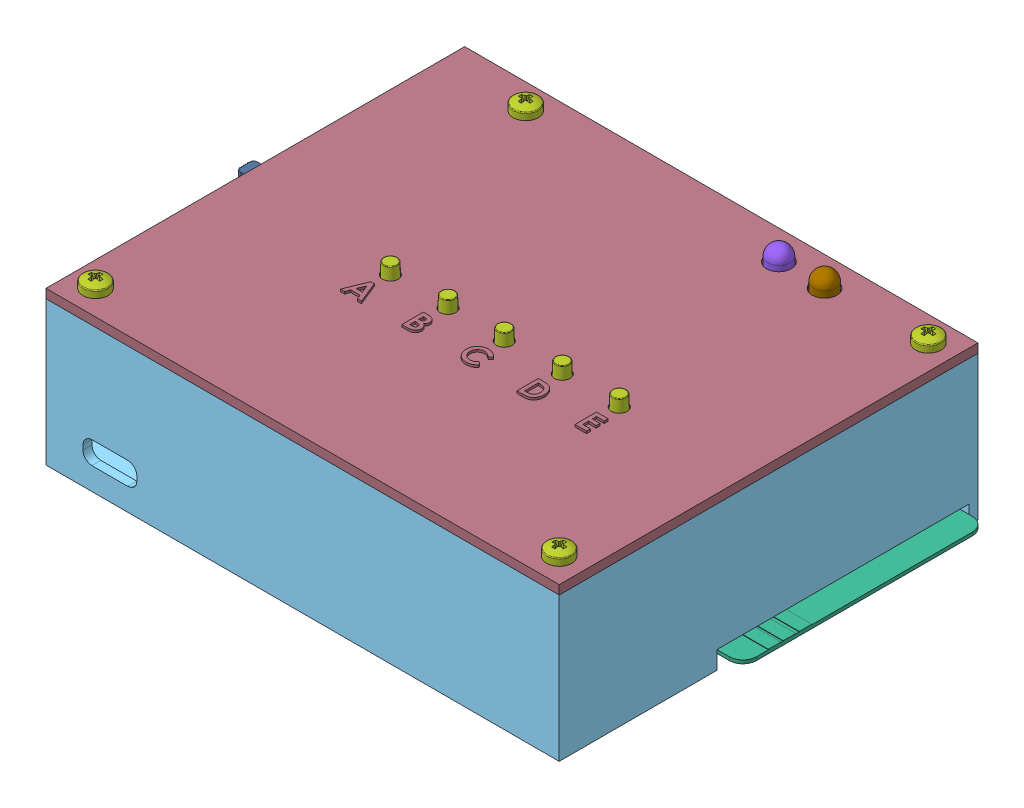
SolidWorks assembly Big_Assembly, configuration Default. Lengths in mm.
Overall size (123.61 37.68 93).
220 component instances, 55 part files, 99 mates.
Components (placement in the parent):
- ESP8266 v7-1: ESP8266 v7 [Default] at (-1.1537 3.2563 1.1041) x (0 0 -1) z (1 0 0) size (25.55 14.09 48.82)
  - ESP8266 v7-1: ESP8266 v7 [Default] at origin size (16.52 3.75 40.51)
  - micro usb v1-1: micro usb v1 [Default] at (12.6689 12.0548 1.95) x (0 -1 0) z (-1 0 0) size (3.25 6.18 8.01)
    - micro usb shell-1: micro usb shell [Default] at (10.11 -1.95 -0.7124) x (0 0 -1) z (0 1 0) size (8.01 2.95 5.63)
    - micro usb internal-1: micro usb internal [Default] at (10.36 -1.95 -0.7124) x (0 0 -1) z (0 1 0) size (6.9 2.9 4)
    - micro usb contact-1: micro usb contact [Default] at (10.36 -2.05 -2.0124) x (0 0 -1) z (0 1 0) size (0.2 1.3 4.65)
    - micro usb contact-2: micro usb contact [Default] at (10.36 -2.05 -1.3624) x (0 0 -1) z (0 1 0) size (0.2 1.3 4.65)
    - micro usb contact-3: micro usb contact [Default] at (10.36 -2.05 -0.7124) x (0 0 -1) z (0 1 0) size (0.2 1.3 4.65)
    - micro usb contact-4: micro usb contact [Default] at (10.36 -2.05 -0.0624) x (0 0 -1) z (0 1 0) size (0.2 1.3 4.65)
    - micro usb contact-5: micro usb contact [Default] at (10.36 -2.05 0.5876) x (0 0 -1) z (0 1 0) size (0.2 1.3 4.65)
  - switch v1-1: switch v1 [Default] at (-4.6798 0 12.1544) x (1 0 0) z (0 1 0) size (3 4.6 1.85)
  - switch v1 (1)-1: switch v1 (1) [Default] at (8.3273 0 12.1544) x (1 0 0) z (0 1 0) size (3 4.6 1.85)
  - Placa Base-1: Placa Base [Default] at origin size (25.55 11.43 48.19)
    - Placa Base-1: Placa Base [Default] at origin size (25.55 1.6 48.19)
    - Pin Header 1x15 TH Pitch 2.54mm v3 v1-1: Pin Header 1x15 TH Pitch 2.54mm v3 v1 [Default] at (24.996 0.1484 -10.5049) x (0 0 -1) z (0 1 0) size (38.1 2.59 11.43)
      - asm_pin-1: asm_pin [Default] at (-4.318 1.27 0.0014) x (1 0 0) z (0 0 -1) size (2.54 2.59 11.43)
        - spacer-1: spacer [Default] at origin size (2.54 2.59 2.54)
        - pin-1: pin [Default] at origin size (0.64 0.64 11.43)
      - asm_pin_1-1: asm_pin_1 [Default] at (-1.778 1.27 0.0014) x (1 0 0) z (0 0 -1) size (2.54 2.59 11.43)
        - spacer-1: spacer [Default] at origin size (2.54 2.59 2.54)
        - pin-1: pin [Default] at origin size (0.64 0.64 11.43)
      - asm_pin_2-1: asm_pin_2 [Default] at (0.762 1.27 0.0014) x (1 0 0) z (0 0 -1) size (2.54 2.59 11.43)
        - spacer-1: spacer [Default] at origin size (2.54 2.59 2.54)
        - pin-1: pin [Default] at origin size (0.64 0.64 11.43)
      - asm_pin_3-1: asm_pin_3 [Default] at (3.302 1.27 0.0014) x (1 0 0) z (0 0 -1) size (2.54 2.59 11.43)
        - spacer-1: spacer [Default] at origin size (2.54 2.59 2.54)
        - pin-1: pin [Default] at origin size (0.64 0.64 11.43)
      - asm_pin_4-1: asm_pin_4 [Default] at (5.842 1.27 0.0014) x (1 0 0) z (0 0 -1) size (2.54 2.59 11.43)
        - spacer-1: spacer [Default] at origin size (2.54 2.59 2.54)
        - pin-1: pin [Default] at origin size (0.64 0.64 11.43)
      - asm_pin_5-1: asm_pin_5 [Default] at (8.382 1.27 0.0014) x (1 0 0) z (0 0 -1) size (2.54 2.59 11.43)
        - spacer-1: spacer [Default] at origin size (2.54 2.59 2.54)
        - pin-1: pin [Default] at origin size (0.64 0.64 11.43)
      - asm_pin_6-1: asm_pin_6 [Default] at (10.922 1.27 0.0014) x (1 0 0) z (0 0 -1) size (2.54 2.59 11.43)
        - spacer-1: spacer [Default] at origin size (2.54 2.59 2.54)
        - pin-1: pin [Default] at origin size (0.64 0.64 11.43)
      - asm_pin_7-1: asm_pin_7 [Default] at (13.462 1.27 0.0014) x (1 0 0) z (0 0 -1) size (2.54 2.59 11.43)
        - spacer-1: spacer [Default] at origin size (2.54 2.59 2.54)
        - pin-1: pin [Default] at origin size (0.64 0.64 11.43)
      - asm_pin_8-1: asm_pin_8 [Default] at (16.002 1.27 0.0014) x (1 0 0) z (0 0 -1) size (2.54 2.59 11.43)
        - spacer-1: spacer [Default] at origin size (2.54 2.59 2.54)
        - pin-1: pin [Default] at origin size (0.64 0.64 11.43)
      - asm_pin_9-1: asm_pin_9 [Default] at (18.542 1.27 0.0014) x (1 0 0) z (0 0 -1) size (2.54 2.59 11.43)
        - spacer-1: spacer [Default] at origin size (2.54 2.59 2.54)
        - pin-1: pin [Default] at origin size (0.64 0.64 11.43)
      - asm_pin_10-1: asm_pin_10 [Default] at (21.082 1.27 0.0014) x (1 0 0) z (0 0 -1) size (2.54 2.59 11.43)
        - spacer-1: spacer [Default] at origin size (2.54 2.59 2.54)
        - pin-1: pin [Default] at origin size (0.64 0.64 11.43)
      - asm_pin_11-1: asm_pin_11 [Default] at (23.622 1.27 0.0014) x (1 0 0) z (0 0 -1) size (2.54 2.59 11.43)
        - spacer-1: spacer [Default] at origin size (2.54 2.59 2.54)
        - pin-1: pin [Default] at origin size (0.64 0.64 11.43)
      - asm_pin_12-1: asm_pin_12 [Default] at (26.1619 1.27 0.0014) x (1 0 0) z (0 0 -1) size (2.54 2.59 11.43)
        - spacer-1: spacer [Default] at origin size (2.54 2.59 2.54)
        - pin-1: pin [Default] at origin size (0.64 0.64 11.43)
      - asm_pin_13-1: asm_pin_13 [Default] at (28.702 1.27 0.0014) x (1 0 0) z (0 0 -1) size (2.54 2.59 11.43)
        - spacer-1: spacer [Default] at origin size (2.54 2.59 2.54)
        - pin-1: pin [Default] at origin size (0.64 0.64 11.43)
      - asm_pin_14-1: asm_pin_14 [Default] at (31.242 1.27 0.0014) x (1 0 0) z (0 0 -1) size (2.54 2.59 11.43)
        - spacer-1: spacer [Default] at origin size (2.54 2.59 2.54)
        - pin-1: pin [Default] at origin size (0.64 0.64 11.43)
    - Pin Header 1x15 TH Pitch 2.54mm v3 v1 (1) (1)-1: Pin Header 1x15 TH Pitch 2.54mm v3 v1 (1) (1) [Default] at (2.7074 0.1484 -10.5049) x (0 0 -1) z (0 1 0) size (38.1 2.59 11.43)
      - asm_pin (1) (1)-1: asm_pin (1) (1) [Default] at (-4.318 1.27 0.0014) x (1 0 0) z (0 0 -1) size (2.54 2.59 11.43)
        - spacer (1) (1)-1: spacer (1) (1) [Default] at origin size (2.54 2.59 2.54)
        - pin (1) (1)-1: pin (1) (1) [Default] at origin size (0.64 0.64 11.43)
      - asm_pin (1) (1)_1-1: asm_pin (1) (1)_1 [Default] at (-1.778 1.27 0.0014) x (1 0 0) z (0 0 -1) size (2.54 2.59 11.43)
        - spacer (1) (1)-1: spacer (1) (1) [Default] at origin size (2.54 2.59 2.54)
        - pin (1) (1)-1: pin (1) (1) [Default] at origin size (0.64 0.64 11.43)
      - asm_pin (1) (1)_2-1: asm_pin (1) (1)_2 [Default] at (0.762 1.27 0.0014) x (1 0 0) z (0 0 -1) size (2.54 2.59 11.43)
        - spacer (1) (1)-1: spacer (1) (1) [Default] at origin size (2.54 2.59 2.54)
        - pin (1) (1)-1: pin (1) (1) [Default] at origin size (0.64 0.64 11.43)
      - asm_pin (1) (1)_3-1: asm_pin (1) (1)_3 [Default] at (3.302 1.27 0.0014) x (1 0 0) z (0 0 -1) size (2.54 2.59 11.43)
        - spacer (1) (1)-1: spacer (1) (1) [Default] at origin size (2.54 2.59 2.54)
        - pin (1) (1)-1: pin (1) (1) [Default] at origin size (0.64 0.64 11.43)
      - asm_pin (1) (1)_4-1: asm_pin (1) (1)_4 [Default] at (5.842 1.27 0.0014) x (1 0 0) z (0 0 -1) size (2.54 2.59 11.43)
        - spacer (1) (1)-1: spacer (1) (1) [Default] at origin size (2.54 2.59 2.54)
        - pin (1) (1)-1: pin (1) (1) [Default] at origin size (0.64 0.64 11.43)
      - asm_pin (1) (1)_5-1: asm_pin (1) (1)_5 [Default] at (8.382 1.27 0.0014) x (1 0 0) z (0 0 -1) size (2.54 2.59 11.43)
        - spacer (1) (1)-1: spacer (1) (1) [Default] at origin size (2.54 2.59 2.54)
        - pin (1) (1)-1: pin (1) (1) [Default] at origin size (0.64 0.64 11.43)
      - asm_pin (1) (1)_6-1: asm_pin (1) (1)_6 [Default] at (10.922 1.27 0.0014) x (1 0 0) z (0 0 -1) size (2.54 2.59 11.43)
        - spacer (1) (1)-1: spacer (1) (1) [Default] at origin size (2.54 2.59 2.54)
        - pin (1) (1)-1: pin (1) (1) [Default] at origin size (0.64 0.64 11.43)
      - asm_pin (1) (1)_7-1: asm_pin (1) (1)_7 [Default] at (13.462 1.27 0.0014) x (1 0 0) z (0 0 -1) size (2.54 2.59 11.43)
        - spacer (1) (1)-1: spacer (1) (1) [Default] at origin size (2.54 2.59 2.54)
        - pin (1) (1)-1: pin (1) (1) [Default] at origin size (0.64 0.64 11.43)
      - asm_pin (1) (1)_8-1: asm_pin (1) (1)_8 [Default] at (16.002 1.27 0.0014) x (1 0 0) z (0 0 -1) size (2.54 2.59 11.43)
        - spacer (1) (1)-1: spacer (1) (1) [Default] at origin size (2.54 2.59 2.54)
        - pin (1) (1)-1: pin (1) (1) [Default] at origin size (0.64 0.64 11.43)
      - asm_pin (1) (1)_9-1: asm_pin (1) (1)_9 [Default] at (18.542 1.27 0.0014) x (1 0 0) z (0 0 -1) size (2.54 2.59 11.43)
        - spacer (1) (1)-1: spacer (1) (1) [Default] at origin size (2.54 2.59 2.54)
        - pin (1) (1)-1: pin (1) (1) [Default] at origin size (0.64 0.64 11.43)
      - asm_pin (1) (1)_10-1: asm_pin (1) (1)_10 [Default] at (21.082 1.27 0.0014) x (1 0 0) z (0 0 -1) size (2.54 2.59 11.43)
        - spacer (1) (1)-1: spacer (1) (1) [Default] at origin size (2.54 2.59 2.54)
        - pin (1) (1)-1: pin (1) (1) [Default] at origin size (0.64 0.64 11.43)
      - asm_pin (1) (1)_11-1: asm_pin (1) (1)_11 [Default] at (23.622 1.27 0.0014) x (1 0 0) z (0 0 -1) size (2.54 2.59 11.43)
        - spacer (1) (1)-1: spacer (1) (1) [Default] at origin size (2.54 2.59 2.54)
        - pin (1) (1)-1: pin (1) (1) [Default] at origin size (0.64 0.64 11.43)
      - asm_pin (1) (1)_12-1: asm_pin (1) (1)_12 [Default] at (26.1619 1.27 0.0014) x (1 0 0) z (0 0 -1) size (2.54 2.59 11.43)
        - spacer (1) (1)-1: spacer (1) (1) [Default] at origin size (2.54 2.59 2.54)
        - pin (1) (1)-1: pin (1) (1) [Default] at origin size (0.64 0.64 11.43)
      - asm_pin (1) (1)_13-1: asm_pin (1) (1)_13 [Default] at (28.702 1.27 0.0014) x (1 0 0) z (0 0 -1) size (2.54 2.59 11.43)
        - spacer (1) (1)-1: spacer (1) (1) [Default] at origin size (2.54 2.59 2.54)
        - pin (1) (1)-1: pin (1) (1) [Default] at origin size (0.64 0.64 11.43)
      - asm_pin (1) (1)_14-1: asm_pin (1) (1)_14 [Default] at (31.242 1.27 0.0014) x (1 0 0) z (0 0 -1) size (2.54 2.59 11.43)
        - spacer (1) (1)-1: spacer (1) (1) [Default] at origin size (2.54 2.59 2.54)
        - pin (1) (1)-1: pin (1) (1) [Default] at origin size (0.64 0.64 11.43)
  - TSOP-5 v4 v1-1: TSOP-5 v4 v1 [Default] at (-0.2513 -0.1563 0.1159) x (-0.013485 0 0.999909) z (0 1 0) size (6.03 5.43 2.12)
  - TSOP-5 v4 v1 (1)-1: TSOP-5 v4 v1 (1) [Default] at (20.2211 1.5986 -10.6444) x (1 0 0) z (0 1 0) size (3.02 2.71 1.06)
  - TSOP-5 v4 v1 (1) (1)-1: TSOP-5 v4 v1 (1) (1) [Default] at (20.2211 1.5625 -17.2293) x (-1 0 0) z (0 1 0) size (3.02 2.71 1.06)
  - Component41-1: Component41 [Default] at origin size (2.26 1.3 15)
  - R0805-NO v1-1: R0805-NO v1 [Default] at (8.8909 1.5658 -11.5498) x (1 0 0) z (0 1 0) size (2.33 1.37 0.46)
  - R0805-NO v1-2: R0805-NO v1 [Default] at (5.3832 1.5658 -9.5734) x (0 0 1) z (0 1 0) size (2.33 1.37 0.46)
  - R0805-NO v1-3: R0805-NO v1 [Default] at (4.7384 1.5658 -14.0063) x (0 0 1) z (0 1 0) size (2.33 1.37 0.46)
  - R0805-NO v1-4: R0805-NO v1 [Default] at (21.2208 1.5658 -14.0063) x (0 0 1) z (0 1 0) size (2.33 1.37 0.46)
  - R0805-NO v1-5: R0805-NO v1 [Default] at (19.6088 1.5658 -14.0063) x (0 0 1) z (0 1 0) size (2.33 1.37 0.46)
  - R0805-NO v1-6: R0805-NO v1 [Default] at (17.9968 1.5658 -14.0063) x (0 0 1) z (0 1 0) size (2.33 1.37 0.46)
  - R0805-NO v1-7: R0805-NO v1 [Default] at (16.3849 1.5658 -14.0063) x (0 0 1) z (0 1 0) size (2.33 1.37 0.46)
  - R0805-NO v1-8: R0805-NO v1 [Default] at (14.6923 1.5658 -14.0063) x (0 0 1) z (0 1 0) size (2.33 1.37 0.46)
  - R0805-NO v1-9: R0805-NO v1 [Default] at (13.04 1.5658 -14.0063) x (0 0 1) z (0 1 0) size (2.33 1.37 0.46)
  - R0805-NO v1-10: R0805-NO v1 [Default] at (11.5893 1.5658 -14.0063) x (0 0 1) z (0 1 0) size (2.33 1.37 0.46)
  - R0805-NO v1-11: R0805-NO v1 [Default] at (9.8564 1.5658 -14.0063) x (0 0 1) z (0 1 0) size (2.33 1.37 0.46)
  - R0805-NO v1-12: R0805-NO v1 [Default] at (8.1638 1.5658 -14.0063) x (0 0 1) z (0 1 0) size (2.33 1.37 0.46)
  - R0805-NO v1-13: R0805-NO v1 [Default] at (6.4713 1.5658 -14.0063) x (0 0 1) z (0 1 0) size (2.33 1.37 0.46)
  - R0805-NO v1 (1)-1: R0805-NO v1 (1) [Default] at (8.4415 1.5658 -9.3168) x (0 0 1) z (0 1 0) size (1.63 0.96 0.32)
  - R0805-NO v1 (1)-2: R0805-NO v1 (1) [Default] at (9.9358 1.5658 -9.3168) x (0 0 1) z (0 1 0) size (1.63 0.96 0.32)
  - R0805-NO v1 (1) (1)-1: R0805-NO v1 (1) (1) [Default] at (8.597 1.5658 -17.758) x (0 0 1) z (0 1 0) size (3.26 1.92 0.63)
  - R0805-NO v1 (1) (2)-1: R0805-NO v1 (1) (2) [Default] at (4.6179 1.5658 -48.9696) x (0 0 1) z (0 1 0) size (4.89 2.88 0.95)
  - R0805-NO v1 (1) (3)-1: R0805-NO v1 (1) (3) [Default] at (8.3907 1.5658 -21.9299) x (1 0 0) z (0 1 0) size (1.63 0.96 0.32)
  - Cuerpo Microprocesador v1-1: Cuerpo Microprocesador v1 [Default] at (13.4174 0.8784 -8.5282) size (5.17 0.51 5.78)
- PCB-1: PCB [Default] at (-59.3712 -0.7038 116.7614) x (1 0 0) z (0 1 0) size (95.23 55.55 12.97)
  - PCB Component-1: PCB Component [Default] at origin size (95.23 55.55 12.97)
    - Board-1: Board [Default] at origin size (95.23 55.55 1.57)
    - 4532N-1: 4532N [Default] at (74.93 115.57 1.57) x (-1 0 0) z (0 0 1) size (19.81 8.66 8.71)
    - LED3MM-1: LED3MM [Default] at (87.63 143.51 1.57) size (3.86 1.32 1.09) (hidden)
    - LED3MM-2: LED3MM [Default] at (77.47 143.51 1.57) size (3.86 1.32 1.09) (hidden)
    - 1X02-1: 1X02 [Default] at (27.686 95.123 1.57) size (5.08 2.54 12.64)
    - 510-1: 510 [Default] at (35.306 105.664 1.57) x (-1 0 0) z (0 0 1) size (8.94 1.32 1.06) (hidden)
    - 510-2: 510 [Default] at (48.006 105.664 1.57) x (-1 0 0) z (0 0 1) size (8.94 1.32 1.06) (hidden)
    - 510-3: 510 [Default] at (60.706 105.664 1.57) x (-1 0 0) z (0 0 1) size (8.94 1.32 1.06) (hidden)
    - 510-4: 510 [Default] at (73.406 105.664 1.57) x (-1 0 0) z (0 0 1) size (8.94 1.32 1.06) (hidden)
    - 510-5: 510 [Default] at (86.106 105.537 1.57) x (-1 0 0) z (0 0 1) size (8.94 1.32 1.06) (hidden)
    - 510-6: 510 [Default] at (88.9 134.62 1.57) x (0 -1 0) z (0 0 1) size (8.94 1.32 1.06) (hidden)
    - 510-7: 510 [Default] at (78.74 134.62 1.57) x (0 -1 0) z (0 0 1) size (8.94 1.32 1.06) (hidden)
    - FSM8JH-1: FSM8JH [Default] at (36.83 97.79 1.57) x (0 1 0) z (0 0 1) size (8.7 6 0.1) (hidden)
    - FSM8JH-2: FSM8JH [Default] at (49.53 97.79 1.57) x (0 1 0) z (0 0 1) size (8.7 6 0.1) (hidden)
    - FSM8JH-3: FSM8JH [Default] at (62.23 97.79 1.57) x (0 1 0) z (0 0 1) size (8.7 6 0.1) (hidden)
    - FSM8JH-4: FSM8JH [Default] at (74.93 97.79 1.57) x (0 1 0) z (0 0 1) size (8.7 6 0.1) (hidden)
    - FSM8JH-5: FSM8JH [Default] at (87.63 97.79 1.57) x (0 1 0) z (0 0 1) size (8.7 6 0.1) (hidden)
    - ESP12E_DEVKIT-1: ESP12E_DEVKIT [Default] at (34.29 128.27 1.57) x (0 1 0) z (0 0 1) size (25.4 48.26 0.1) (hidden)
- Tactal Switch -Thru (6mmx 6mmx13.0mm)-1: Tactal Switch -Thru (6mmx 6mmx13.0mm) [Default] at (-22.5479 0.8662 18.8965) x (0 0 -1) z (0 1 0) size (8.37 5.99 16.18)
- Tactal Switch -Thru (6mmx 6mmx13.0mm)-2: Tactal Switch -Thru (6mmx 6mmx13.0mm) [Default] at (-9.7433 0.8662 18.9061) x (0 0 1) z (0 1 0) size (8.37 5.99 16.18)
- Tactal Switch -Thru (6mmx 6mmx13.0mm)-3: Tactal Switch -Thru (6mmx 6mmx13.0mm) [Default] at (2.8237 0.8662 18.9755) x (0 0 1) z (0 1 0) size (8.37 5.99 16.18)
- Tactal Switch -Thru (6mmx 6mmx13.0mm)-4: Tactal Switch -Thru (6mmx 6mmx13.0mm) [Default] at (15.6176 0.8662 18.8925) x (0 0 1) z (0 1 0) size (8.37 5.99 16.18)
- Tactal Switch -Thru (6mmx 6mmx13.0mm)-5: Tactal Switch -Thru (6mmx 6mmx13.0mm) [Default] at (28.2908 0.8662 18.8988) x (0 0 1) z (0 1 0) size (8.37 5.99 16.18)
- LED 5mm red-1: LED 5mm red [Default] at (18.0988 6.0477 -26.7486) x (0 0 -1) z (0 1 0) size (5.8 5.4 33.7)
- LED 5mm green-1: LED 5mm green [Default] at (28.2588 6.2313 -26.7486) x (0 0 -1) z (0 1 0) size (5.8 5.4 33.7)
- RFID-1: RFID [Default] at (7.3932 47.7062 1.4558) x (0 0 -1) z (0 -1 0) size (40 60 11.54)
  - Part1_1-1: Part1_1 [Default] at (-16.3439 30.7712 59.45) size (40 60 2)
  - Part10-1: Part10 [Default] at (20.709 20.1029 60.45) x (0 1 0) z (0 0 1) size (10.67 3.05 5.63)
  - User Library-S-PWSON-N12-1: User Library-S-PWSON-N12 [Default] at (4.1233 20.047 60.45) x (1 0 0) z (0 -1 0) size (3 0.8 3)
  - User Library-Header_Male_8Pin-1: User Library-Header_Male_8Pin [Default] at (12.9823 28.5305 62.74) x (-1 0 0) z (0 0 -1) size (20.32 2.49 11.54) (hidden)
  - User Library-SMD Ceramic Capacitors_0603 (1608)_CH-1: User Library-SMD Ceramic Capacitors_0603 (1608)_CH [Default] at (-3.9959 5.9247 60.9127) size (1.72 0.91 0.98)
  - User Library-SMD Ceramic Capacitors_0603 (1608)_CH-2: User Library-SMD Ceramic Capacitors_0603 (1608)_CH [Default] at (-1.0806 5.9034 60.9127) size (1.72 0.91 0.98)
  - User Library-SMD Ceramic Capacitors_0603 (1608)_CH-3: User Library-SMD Ceramic Capacitors_0603 (1608)_CH [Default] at (2.2282 5.9089 60.9127) size (1.72 0.91 0.98)
  - User Library-SMD Ceramic Capacitors_0603 (1608)_CH-4: User Library-SMD Ceramic Capacitors_0603 (1608)_CH [Default] at (5.214 5.921 60.9127) size (1.72 0.91 0.98)
  - User Library-SMD Ceramic Capacitors_0603 (1608)_CH-5: User Library-SMD Ceramic Capacitors_0603 (1608)_CH [Default] at (8.193 5.9188 60.9127) size (1.72 0.91 0.98)
  - User Library-SMD Ceramic Capacitors_0603 (1608)_CH-6: User Library-SMD Ceramic Capacitors_0603 (1608)_CH [Default] at (11.3855 5.9271 60.9127) size (1.72 0.91 0.98)
  - User Library-SMD Ceramic Capacitors_0603 (1608)_CH-7: User Library-SMD Ceramic Capacitors_0603 (1608)_CH [Default] at (16.3593 23.3789 60.9127) size (1.72 0.91 0.98)
  - User Library-SMD Ceramic Capacitors_0603 (1608)_CH-8: User Library-SMD Ceramic Capacitors_0603 (1608)_CH [Default] at (16.3593 21.3117 60.9127) size (1.72 0.91 0.98)
  - User Library-SMD Ceramic Capacitors_0603 (1608)_CH-9: User Library-SMD Ceramic Capacitors_0603 (1608)_CH [Default] at (13.4136 25.6528 60.9127) size (1.72 0.91 0.98)
  - User Library-SMD Ceramic Capacitors_0603 (1608)_CH-10: User Library-SMD Ceramic Capacitors_0603 (1608)_CH [Default] at (13.517 19.0895 60.9127) size (1.72 0.91 0.98)
  - Part8-1: Part8 [Default] at (13.517 23.4826 60.704) size (1.6 0.81 0.51)
  - Part8-2: Part8 [Default] at (13.517 21.3121 60.704) size (1.6 0.81 0.51)
  - User Library-SMD Ceramic Capacitors_0603 (1608)_CH-11: User Library-SMD Ceramic Capacitors_0603 (1608)_CH [Default] at (-5.0547 25.4542 60.9127) size (1.72 0.91 0.98)
  - User Library-SMD Ceramic Capacitors_0603 (1608)_CH-12: User Library-SMD Ceramic Capacitors_0603 (1608)_CH [Default] at (-5.0547 21.4355 60.9127) size (1.72 0.91 0.98)
  - User Library-SMD Ceramic Capacitors_0603 (1608)_CH-13: User Library-SMD Ceramic Capacitors_0603 (1608)_CH [Default] at (-5.0547 19.367 60.9127) size (1.72 0.91 0.98)
  - Part8-3: Part8 [Default] at (-5.0547 23.3861 60.704) size (1.6 0.81 0.51)
  - Part8-4: Part8 [Default] at (-10.0418 25.4159 60.704) size (1.6 0.81 0.51)
  - Part8-5: Part8 [Default] at (-10.0625 23.4569 60.704) size (1.6 0.81 0.51)
  - Part8-6: Part8 [Default] at (-10.0541 27.4204 60.704) size (1.6 0.81 0.51)
- 1X08-1: 1X08 [Default] at (35.9237 -11.7438 -2.6054) x (0 0 -1) z (0 1 0) size (20.32 2.54 11.34)
- zl262-8s_p2-54_l20-8_w2-54_h8-5-1: zl262-8s_p2-54_l20-8_w2-54_h8-5 [Default] at (35.8937 -0.7038 -2.6065) x (0 0 -1) z (-1 0 0) size (20.82 11.5 2.54)
- rcil-h_p9_l6-25_d2-25_h2-25-1: rcil-h_p9_l6-25_d2-25_h2-25 [Default] at (29.4077 1.2962 -17.6991) x (0 0 1) z (-1 0 0) size (9.61 6.26 2.27)
- rcil-h_p9_l6-25_d2-25_h2-25-2: rcil-h_p9_l6-25_d2-25_h2-25 [Default] at (19.3359 1.2962 -17.7732) x (0 0 1) z (-1 0 0) size (9.61 6.26 2.27)
- rcil-h_p9_l6-25_d2-25_h2-25-3: rcil-h_p9_l6-25_d2-25_h2-25 [Default] at (-24.0285 1.2962 11.1118) size (9.61 6.26 2.27)
- rcil-h_p9_l6-25_d2-25_h2-25-4: rcil-h_p9_l6-25_d2-25_h2-25 [Default] at (-11.419 1.2962 11.0712) size (9.61 6.26 2.27)
- rcil-h_p9_l6-25_d2-25_h2-25-5: rcil-h_p9_l6-25_d2-25_h2-25 [Default] at (1.2877 1.2962 11.0664) size (9.61 6.26 2.27)
- rcil-h_p9_l6-25_d2-25_h2-25-6: rcil-h_p9_l6-25_d2-25_h2-25 [Default] at (14.1377 1.2962 11.1099) size (9.61 6.26 2.27)
- rcil-h_p9_l6-25_d2-25_h2-25-7: rcil-h_p9_l6-25_d2-25_h2-25 [Default] at (26.7851 1.2962 11.2192) size (9.61 6.26 2.27)
- bat_shield-1: bat_shield [Default] at (-3.1118 -5.3538 35.8784) size (106.11 24.61 29.5)
  - wemos_board-1: wemos_board [Default] at (-11.1526 -8.39 7.9122) size (100 2 29.5)
  - battery_holder-1: battery_holder [Default] at (-6.5793 -6.39 5.643) size (75 21 21)
  - usb-1: usb [Default] at (49.6257 -8.09 -16.112) x (0 0 1) z (-1 0 0) size (15.78 11.14 14.45)
  - MicroUSB_Pinboard_5_Pins-2: MicroUSB_Pinboard_5_Pins [Standard] at (-41.6369 7.11 12.643) x (0 0 1) z (0 -1 0) size (11.21 7.77 3.44)
- Battery Samsung ICR 18650 -22E-1: Battery Samsung ICR 18650 -22E [Default] at (20.3473 -3.9534 29.621) x (-1 0 0) z (0 -0.924225 -0.381849) size (65 18 18)
- card_slot-1: card_slot [Default] at (-9.6486 -16.7438 -0.5651) x (1 0 0) z (0 0 -1) size (114 32 93)
- Iso Card Magnetic Stripe-1: Iso Card Magnetic Stripe [Default] at (17.5482 -20.3638 -3.4886) x (1 0 0) z (0 -1 0) size (85.6 53.98 0.96)
- ISO 7045 - M3 x 6 - Z - 6S-1: ISO 7045 - M3 x 6 - Z - 6S [ISO 7045 - M3 x 6 - Z - 6S] at (-51.7512 3.2662 -28.0186) x (0 -1 0) z (0.546944 0 -0.837169) size (8.35 5.6 5.6)
- ISO 7045 - M3 x 6 - Z - 6S-2: ISO 7045 - M3 x 6 - Z - 6S [ISO 7045 - M3 x 6 - Z - 6S] at (-51.7512 3.2662 22.7814) x (0 -1 0) z (1 0 0) size (8.35 5.6 5.6)
- ISO 7045 - M3 x 6 - Z - 6S-3: ISO 7045 - M3 x 6 - Z - 6S [ISO 7045 - M3 x 6 - Z - 6S] at (38.4188 3.2662 22.7814) x (0 -1 0) z (1 0 0) size (8.35 5.6 5.6)
- ISO 7045 - M3 x 6 - Z - 6S-4: ISO 7045 - M3 x 6 - Z - 6S [ISO 7045 - M3 x 6 - Z - 6S] at (38.4188 3.2662 -28.0186) x (0 -1 0) z (0.383049 0 -0.923728) size (8.35 5.6 5.6)
- ISO 7045 - M3 x 6 - Z - 6S-5: ISO 7045 - M3 x 6 - Z - 6S [ISO 7045 - M3 x 6 - Z - 6S] at (-52.2912 -9.3438 28.7714) x (0 -1 0) z (0 0 1) size (8.35 5.6 5.6)
- ISO 7045 - M3 x 6 - Z - 6S-7: ISO 7045 - M3 x 6 - Z - 6S [ISO 7045 - M3 x 6 - Z - 6S] at (43.7088 -9.3438 54.2714) x (0 -1 0) z (0 0 -1) size (8.35 5.6 5.6)
- ISO 7045 - M3 x 6 - Z - 6S-8: ISO 7045 - M3 x 6 - Z - 6S [ISO 7045 - M3 x 6 - Z - 6S] at (43.7088 -9.3438 28.7714) x (0 -1 0) z (0 0 1) size (8.35 5.6 5.6)
- ISO 7045 - M2.5 x 3 - Z - 3S-1: ISO 7045 - M2.5 x 3 - Z - 3S [ISO 7045 - M2.5 x 3 - Z - 3S] at (-15.8356 -9.6438 11.7997) x (0 -1 0) z (0 0 1) size (5.05 5 5)
- ISO 7045 - M2.5 x 3 - Z - 3S-2: ISO 7045 - M2.5 x 3 - Z - 3S [ISO 7045 - M2.5 x 3 - Z - 3S] at (-15.8356 -9.6438 -16.2003) x (0 -1 0) z (0 0 1) size (5.05 5 5)
- ISO 7045 - M2.5 x 3 - Z - 3S-3: ISO 7045 - M2.5 x 3 - Z - 3S [ISO 7045 - M2.5 x 3 - Z - 3S] at (22.1644 -9.6438 15.2997) x (0 -1 0) z (0 0 1) size (5.05 5 5)
- 5MS1S102BM1QES-1: 5MS1S102BM1QES [Default] at (-70.3146 6.0062 -18.1424) x (0 0 -1) z (0 -1 0) size (19.56 15.39 6.7)
  - Corps-1: Corps [Default] at (-27.6 12.1333 0) size (12.7 7.15 6.7)
  - Curseur-1: Curseur [Default] at (-27.6 13.1333 0) x (1 0 0) z (0 -1 0) size (6.1 3.86 6.08)
  - Enveloppe-1: Enveloppe [Default] at (-27.6 12.1333 0) x (1 0 0) z (0 -1 0) size (19.56 6.5 5)
  - Broches-1: Broches [Default] at (-27.6 18.4833 0) x (-1 0 0) z (0 1 0) size (10.16 2.03 3.96)
- 1X02-1: 1X02 [Default] at (-31.6852 -11.7438 28.7714) x (1 0 0) z (0 1 0) size (5.08 2.54 12.64)
- top-1: top [Default] at (-8.7368 9.2562 -4.2286) size (114 2.5 93)
- ISO 7045 - M3 x 6 - Z - 6S-10: ISO 7045 - M3 x 6 - Z - 6S [ISO 7045 - M3 x 6 - Z - 6S] at (50.3187 13.6562 54.2714) x (0 -1 0) z (0 0 -1) size (8.35 5.6 5.6)
- ISO 7045 - M3 x 6 - Z - 6S-11: ISO 7045 - M3 x 6 - Z - 6S [ISO 7045 - M3 x 6 - Z - 6S] at (-52.6813 13.6562 54.2714) x (0 -1 0) z (0 0 1) size (8.35 5.6 5.6)
- ISO 7045 - M3 x 6 - Z - 6S-12: ISO 7045 - M3 x 6 - Z - 6S [ISO 7045 - M3 x 6 - Z - 6S] at (50.3187 13.6562 -27.7286) x (0 -1 0) z (0 0 1) size (8.35 5.6 5.6)
- ISO 7045 - M3 x 6 - Z - 6S-13: ISO 7045 - M3 x 6 - Z - 6S [ISO 7045 - M3 x 6 - Z - 6S] at (-39.1227 13.6562 -27.7286) x (0 -1 0) z (0 0 1) size (8.35 5.6 5.6)
- ISO 7045 - M2 x 3 - Z - 3S-1: ISO 7045 - M2 x 3 - Z - 3S [ISO 7045 - M2 x 3 - Z - 3S] at (-59.7813 6.0062 18.2226) x (1 0 0) z (0 -0.086548 0.996248) size (4.57 4 4)
- ISO 7045 - M2 x 3 - Z - 3S-2: ISO 7045 - M2 x 3 - Z - 3S [ISO 7045 - M2 x 3 - Z - 3S] at (-59.7813 6.0062 0.6926) size (4.57 4 4)
Mates (geometry in assembly coordinates):
- Coincident1: coincident: plane of ESP8266 v7-1/Placa Base-1/Pin Header 1x15 TH Pitch 2.54mm v3 v1-1/asm_pin_14-1/spacer-1 through (-42.9008 0.8662 -22.6218) normal (0 -1 0); plane of PCB-1/PCB Component-1/Board-1 through (-6.6762 0.8662 -2.4536) normal (0 1 0)
- Parallel2: parallel aligned: plane of ? through (-1.1537 3.2563 1.1041) normal (1 0 0); plane of PCB-1/PCB Component-1/Board-1 through (40.9388 -0.7038 25.3214) normal (1 0 0)
- Coincident4: coincident: plane of PCB-1/PCB Component-1/Board-1 through (-6.6762 0.8662 -2.4536) normal (0 1 0); plane of Tactal Switch -Thru (6mmx 6mmx13.0mm)-1 through (-22.5479 0.8662 18.8965) normal (0 -1 0)
- Parallel3: parallel anti-aligned: plane of PCB-1/PCB Component-1/Board-1 through (-54.2912 -0.7038 25.3214) normal (0 0 1); plane of Tactal Switch -Thru (6mmx 6mmx13.0mm)-1 through (-25.5451 4.473 15.8358) normal (0 0 -1)
- Coincident5: coincident anti-aligned: plane of PCB-1/PCB Component-1/Board-1 through (-6.6762 0.8662 -2.4536) normal (0 1 0); plane of Tactal Switch -Thru (6mmx 6mmx13.0mm)-2 through (-9.7433 0.8662 18.9061) normal (0 -1 0)
- Parallel4: parallel aligned: plane of PCB-1/PCB Component-1/Board-1 through (-54.2912 -0.7038 25.3214) normal (0 0 1); plane of Tactal Switch -Thru (6mmx 6mmx13.0mm)-2 through (-6.7461 4.473 21.9668) normal (0 0 1)
- Coincident7: coincident anti-aligned: plane of PCB-1/PCB Component-1/Board-1 through (-6.6762 0.8662 -2.4536) normal (0 1 0); plane of Tactal Switch -Thru (6mmx 6mmx13.0mm)-3 through (2.8237 0.8662 18.9755) normal (0 -1 0)
- Parallel5: parallel aligned: plane of PCB-1/PCB Component-1/Board-1 through (-54.2912 -0.7038 25.3214) normal (0 0 1); plane of Tactal Switch -Thru (6mmx 6mmx13.0mm)-3 through (5.8209 4.473 22.0362) normal (0 0 1)
- Coincident9: coincident anti-aligned: plane of PCB-1/PCB Component-1/Board-1 through (-6.6762 0.8662 -2.4536) normal (0 1 0); plane of Tactal Switch -Thru (6mmx 6mmx13.0mm)-4 through (15.6176 0.8662 18.8925) normal (0 -1 0)
- Parallel6: parallel aligned: plane of PCB-1/PCB Component-1/Board-1 through (-54.2912 -0.7038 25.3214) normal (0 0 1); plane of Tactal Switch -Thru (6mmx 6mmx13.0mm)-4 through (18.6148 4.473 21.9532) normal (0 0 1)
- Coincident11: coincident anti-aligned: plane of PCB-1/PCB Component-1/Board-1 through (-6.6762 0.8662 -2.4536) normal (0 1 0); plane of Tactal Switch -Thru (6mmx 6mmx13.0mm)-5 through (28.2908 0.8662 18.8988) normal (0 -1 0)
- Parallel7: parallel aligned: plane of PCB-1/PCB Component-1/Board-1 through (-54.2912 -0.7038 25.3214) normal (0 0 1); plane of Tactal Switch -Thru (6mmx 6mmx13.0mm)-5 through (31.288 4.473 21.9595) normal (0 0 1)
- Parallel8: parallel anti-aligned: plane of PCB-1/PCB Component-1/Board-1 through (-6.6762 0.8662 -2.4536) normal (0 1 0); plane of LED 5mm red-1 through (20.6088 6.0477 -30.1388) normal (0 -1 0)
- Concentric3: concentric anti-aligned: cylinder of PCB-1/PCB Component-1/Board-1 through (19.3688 -0.7038 -26.7486) axis (0 1 0) radius 0.4065; cylinder of LED 5mm red-1 through (19.3688 6.0477 -26.7486) axis (0 -1 0) radius 0.27
- Concentric4: concentric anti-aligned: cylinder of PCB-1/PCB Component-1/Board-1 through (16.8288 -0.7038 -26.7486) axis (0 1 0) radius 0.4065; cylinder of LED 5mm red-1 through (16.8288 6.0477 -26.7486) axis (0 -1 0) radius 0.27
- Concentric5: concentric anti-aligned: cylinder of PCB-1/PCB Component-1/Board-1 through (29.5288 -0.7038 -26.7486) axis (0 1 0) radius 0.4065; cylinder of LED 5mm green-1 through (29.5288 6.2313 -26.7486) axis (0 -1 0) radius 0.27
- Concentric6: concentric anti-aligned: cylinder of PCB-1/PCB Component-1/Board-1 through (26.9888 -0.7038 -26.7486) axis (0 1 0) radius 0.4065; cylinder of LED 5mm green-1 through (26.9888 6.2313 -26.7486) axis (0 -1 0) radius 0.27
- Parallel9: parallel anti-aligned: plane of PCB-1/PCB Component-1/Board-1 through (-6.6762 -0.7038 -2.4536) normal (0 -1 0); plane of RFID-1/Part1_1-1 through (38.1644 -11.7438 17.7997) normal (0 1 0)
- Parallel10: parallel aligned: plane of PCB-1/PCB Component-1/Board-1 through (40.9388 -0.7038 25.3214) normal (1 0 0); plane of RFID-1/Part1_1-1 through (38.1644 -12.7438 17.7997) normal (1 0 0)
- Coincident16: coincident anti-aligned: plane of PCB-1/PCB Component-1/Board-1 through (-6.6762 -0.7038 -2.4536) normal (0 -1 0); plane of 1X08-1 through (21.69 -0.7038 186.4871) normal (0 1 0)
- Parallel11: parallel aligned: plane of PCB-1/PCB Component-1/Board-1 through (40.9388 -0.7038 25.3214) normal (1 0 0); plane of 1X08-1 through (37.1737 -10.4738 -8.9865) normal (1 0 0)
- Coincident18: coincident aligned: plane of RFID-1/User Library-Header_Male_8Pin-1 through (35.6037 -18.0338 -11.8465) normal (0 0 -1); plane of 1X08-1 through (36.2437 -9.2038 -11.8465) normal (0 0 -1)
- Coincident19: coincident aligned: plane of RFID-1/User Library-Header_Male_8Pin-1 through (35.6037 -18.0338 -11.2065) normal (-1 0 0); plane of 1X08-1 through (35.6037 -9.2038 -11.8465) normal (-1 0 0)
- Coincident20: coincident anti-aligned: plane of RFID-1/Part1_1-1 through (38.1289 -3.2438 17.7993) normal (0 1 0); plane of 1X08-1 through (37.1382 -3.2438 -12.797) normal (0 -1 0)
- Coincident21: coincident: plane of PCB-1/PCB Component-1/Board-1 through (-6.6762 -0.7038 -2.4536) normal (0 -1 0); plane of zl262-8s_p2-54_l20-8_w2-54_h8-5-1 through (34.6237 -0.7038 7.8035) normal (0 1 0)
- Parallel12: parallel aligned: plane of PCB-1/PCB Component-1/Board-1 through (40.9388 -0.7038 25.3214) normal (1 0 0); plane of zl262-8s_p2-54_l20-8_w2-54_h8-5-1 through (37.1637 -0.7038 7.8035) normal (1 0 0)
- Coincident24: coincident anti-aligned: plane of RFID-1/Part1_1-1 through (38.1644 -11.7438 17.7997) normal (0 1 0); plane of 1X08-1 through (37.1737 -11.7438 -12.7965) normal (0 -1 0)
- Coincident25: coincident anti-aligned: plane of 1X08-1 through (37.1737 -9.2038 -10.2565) normal (0 1 0); plane of zl262-8s_p2-54_l20-8_w2-54_h8-5-1 through (37.1637 -9.2038 7.8035) normal (0 -1 0)
- Coincident27: coincident anti-aligned: plane of 1X08-1 through (36.2437 -9.2038 -11.2065) normal (1 0 0); plane of zl262-8s_p2-54_l20-8_w2-54_h8-5-1 through (36.2437 -1.6038 -11.1465) normal (-1 0 0)
- Coincident28: coincident anti-aligned: plane of 1X08-1 through (36.2437 -9.2038 -11.8465) normal (0 0 -1); plane of zl262-8s_p2-54_l20-8_w2-54_h8-5-1 through (35.8937 -0.7038 -11.8465) normal (0 0 1)
- Parallel14: parallel anti-aligned: plane of PCB-1/PCB Component-1/Board-1 through (-6.6762 0.8662 -2.4536) normal (0 1 0); plane of rcil-h_p9_l6-25_d2-25_h2-25-1 through (29.4077 -2.7038 -13.1991) normal (0 -1 0)
- Parallel15: parallel anti-aligned: plane of PCB-1/PCB Component-1/Board-1 through (40.9388 -0.7038 -30.2286) normal (0 0 -1); plane of rcil-h_p9_l6-25_d2-25_h2-25-1 through (29.4077 1.2962 -14.5741) normal (0 0 1)
- Parallel16: parallel: plane of PCB-1/PCB Component-1/Board-1 through (40.9388 -0.7038 -30.2286) normal (0 0 -1); plane of rcil-h_p9_l6-25_d2-25_h2-25-2 through (19.3359 1.2962 -14.6482) normal (0 0 1)
- Distance1: distance = 2 mm aligned: plane of rcil-h_p9_l6-25_d2-25_h2-25-1 through (29.4077 -2.7038 -22.1991) normal (0 -1 0); plane of PCB-1/PCB Component-1/Board-1 through (-6.6762 -0.7038 -2.4536) normal (0 -1 0)
- Distance2: distance = 2 mm aligned: plane of rcil-h_p9_l6-25_d2-25_h2-25-2 through (19.3359 -2.7038 -22.2732) normal (0 -1 0); plane of PCB-1/PCB Component-1/Board-1 through (-6.6762 -0.7038 -2.4536) normal (0 -1 0)
- Distance3: distance = 2 mm: plane of rcil-h_p9_l6-25_d2-25_h2-25-3 through (-19.5285 -2.7038 11.1118) normal (0 -1 0); plane of PCB-1/PCB Component-1/Board-1 through (-6.6762 -0.7038 -2.4536) normal (0 -1 0)
- Parallel17: parallel aligned: plane of PCB-1/PCB Component-1/Board-1 through (-54.2912 -0.7038 -30.2286) normal (-1 0 0); plane of rcil-h_p9_l6-25_d2-25_h2-25-3 through (-27.1535 1.2962 11.1118) normal (-1 0 0)
- Distance4: distance = 2 mm aligned: plane of rcil-h_p9_l6-25_d2-25_h2-25-4 through (-15.919 -2.7038 11.0712) normal (0 -1 0); plane of PCB-1/PCB Component-1/Board-1 through (-6.6762 -0.7038 -2.4536) normal (0 -1 0)
- Parallel18: parallel aligned: plane of PCB-1/PCB Component-1/Board-1 through (-54.2912 -0.7038 -30.2286) normal (-1 0 0); plane of rcil-h_p9_l6-25_d2-25_h2-25-4 through (-14.544 1.2962 11.0712) normal (-1 0 0)
- Distance5: distance = 2 mm: plane of rcil-h_p9_l6-25_d2-25_h2-25-5 through (-3.2123 -2.7038 11.0664) normal (0 -1 0); plane of PCB-1/PCB Component-1/Board-1 through (-6.6762 -0.7038 -2.4536) normal (0 -1 0)
- Parallel19: parallel aligned: plane of PCB-1/PCB Component-1/Board-1 through (-54.2912 -0.7038 -30.2286) normal (-1 0 0); plane of rcil-h_p9_l6-25_d2-25_h2-25-5 through (-1.8373 1.2962 11.0664) normal (-1 0 0)
- Parallel20: parallel aligned: plane of PCB-1/PCB Component-1/Board-1 through (-54.2912 -0.7038 -30.2286) normal (-1 0 0); plane of rcil-h_p9_l6-25_d2-25_h2-25-6 through (11.0127 1.2962 11.1099) normal (-1 0 0)
- Distance6: distance = 2 mm aligned: plane of rcil-h_p9_l6-25_d2-25_h2-25-6 through (9.6377 -2.7038 11.1099) normal (0 -1 0); plane of PCB-1/PCB Component-1/Board-1 through (-6.6762 -0.7038 -2.4536) normal (0 -1 0)
- Parallel22: parallel: plane of PCB-1/PCB Component-1/Board-1 through (-54.2912 -0.7038 -30.2286) normal (-1 0 0); plane of rcil-h_p9_l6-25_d2-25_h2-25-7 through (23.6601 1.2962 11.2192) normal (-1 0 0)
- Distance7: distance = 2 mm aligned: plane of rcil-h_p9_l6-25_d2-25_h2-25-7 through (31.2851 -2.7038 11.2192) normal (0 -1 0); plane of PCB-1/PCB Component-1/Board-1 through (-6.6762 -0.7038 -2.4536) normal (0 -1 0)
- Coincident44: coincident anti-aligned: plane of bat_shield-1/battery_holder-1 through (22.5088 -10.1632 41.5214) normal (-1 0 0); plane of Battery Samsung ICR 18650 -22E-1 through (22.5088 -0.2438 41.5214) normal (1 0 0)
- Concentric7: concentric aligned: cylinder of bat_shield-1/battery_holder-1 through (51.6789 -0.2438 41.5214) axis (-1 0 0) radius 9.5; cylinder of Battery Samsung ICR 18650 -22E-1 through (22.5188 -0.2438 41.5214) axis (-1 0 0) radius 9
- Parallel23: parallel anti-aligned: plane of RFID-1/Part1_1-1 through (38.1644 -12.7438 17.7997) normal (0 -1 0); plane of card_slot-1 through (-9.6486 -16.7438 -0.5651) normal (0 1 0)
- Parallel24: parallel aligned: plane of PCB-1/PCB Component-1/Board-1 through (40.9388 -0.7038 25.3214) normal (1 0 0); plane of card_slot-1 through (55.8187 -18.7438 26.7714) normal (1 0 0)
- Distance8: distance = 4 mm anti-aligned: plane of card_slot-1 through (-9.6486 -16.7438 -0.5651) normal (0 1 0); plane of RFID-1/Part1_1-1 through (38.1644 -12.7438 17.7997) normal (0 -1 0)
- Coincident49: coincident aligned: plane of PCB-1/PCB Component-1/Board-1 through (-54.2912 -0.7038 -30.2286) normal (-1 0 0); plane of bat_shield-1/wemos_board-1 through (-54.2912 -11.7438 26.7714) normal (-1 0 0)
- Distance10: distance = 3 mm anti-aligned: plane of bat_shield-1/wemos_board-1 through (-14.2645 -13.7438 43.7906) normal (0 -1 0); plane of card_slot-1 through (-9.6486 -16.7438 -0.5651) normal (0 1 0)
- Coincident52: coincident anti-aligned: plane of card_slot-1 through (27.8187 -20.7438 -30.2286) normal (0 1 0); plane of Iso Card Magnetic Stripe-1 through (17.5482 -20.7438 -3.4886) normal (0 -1 0)
- Distance11: distance = 0.75 mm anti-aligned: plane of Iso Card Magnetic Stripe-1 through (-25.2518 -20.3638 -30.4786) normal (0 0 -1); plane of card_slot-1 through (55.8187 -20.7438 -31.2286) normal (0 0 1)
- Distance12: distance = 4 mm: plane of card_slot-1 through (55.8187 -18.7438 26.7714) normal (1 0 0); line of bat_shield-1/usb-1 through (51.8187 -6.0238 34.3603) axis (0 -1 0)
- Concentric81: concentric aligned: cylinder of PCB-1/PCB Component-1/Board-1 through (-51.7512 -0.7038 -28.0186) axis (0 1 0) radius 1.5; cylinder of ISO 7045 - M3 x 6 - Z - 6S-1 through (-51.7512 28.6662 -28.0186) axis (0 1 0) radius 2.8
- Coincident551: coincident anti-aligned: plane of PCB-1/PCB Component-1/Board-1 through (-6.6762 0.8662 -2.4536) normal (0 1 0); plane of ISO 7045 - M3 x 6 - Z - 6S-1 through (-53.0069 0.8662 -28.839) normal (0 -1 0)
- Concentric91: concentric aligned: cylinder of PCB-1/PCB Component-1/Board-1 through (-51.7512 -0.7038 22.7814) axis (0 1 0) radius 1.5; cylinder of ISO 7045 - M3 x 6 - Z - 6S-2 through (-51.7512 28.6662 22.7814) axis (0 1 0) radius 2.8
- Coincident561: coincident anti-aligned: plane of PCB-1/PCB Component-1/Board-1 through (-6.6762 0.8662 -2.4536) normal (0 1 0); plane of ISO 7045 - M3 x 6 - Z - 6S-2 through (-51.7512 0.8662 21.2814) normal (0 -1 0)
- Concentric101: concentric aligned: cylinder of PCB-1/PCB Component-1/Board-1 through (38.4188 -0.7038 22.7814) axis (0 1 0) radius 1.5; cylinder of ISO 7045 - M3 x 6 - Z - 6S-3 through (38.4188 28.6662 22.7814) axis (0 1 0) radius 2.8
- Coincident571: coincident anti-aligned: plane of PCB-1/PCB Component-1/Board-1 through (-6.6762 0.8662 -2.4536) normal (0 1 0); plane of ISO 7045 - M3 x 6 - Z - 6S-3 through (38.4188 0.8662 21.2814) normal (0 -1 0)
- Concentric111: concentric aligned: cylinder of PCB-1/PCB Component-1/Board-1 through (38.4188 -0.7038 -28.0186) axis (0 1 0) radius 1.5; cylinder of ISO 7045 - M3 x 6 - Z - 6S-4 through (38.4188 28.6662 -28.0186) axis (0 1 0) radius 2.8
- Coincident581: coincident anti-aligned: plane of PCB-1/PCB Component-1/Board-1 through (-6.6762 0.8662 -2.4536) normal (0 1 0); plane of ISO 7045 - M3 x 6 - Z - 6S-4 through (37.0333 0.8662 -28.5932) normal (0 -1 0)
- Concentric121: concentric aligned: cylinder of bat_shield-1/wemos_board-1 through (-52.2912 -17.9864 28.7714) axis (0 1 0) radius 1.5; cylinder of ISO 7045 - M3 x 6 - Z - 6S-5 through (-52.2912 16.0562 28.7714) axis (0 1 0) radius 2.8
- Coincident591: coincident anti-aligned: plane of bat_shield-1/wemos_board-1 through (-14.2645 -11.7438 43.7906) normal (0 1 0); plane of ISO 7045 - M3 x 6 - Z - 6S-5 through (-50.7912 -11.7438 28.7714) normal (0 -1 0)
- Concentric141: concentric aligned: cylinder of bat_shield-1/wemos_board-1 through (43.7088 -17.9864 54.2714) axis (0 1 0) radius 1.5; cylinder of ISO 7045 - M3 x 6 - Z - 6S-7 through (43.7088 16.0562 54.2714) axis (0 1 0) radius 2.8
- Coincident611: coincident anti-aligned: plane of bat_shield-1/wemos_board-1 through (-14.2645 -11.7438 43.7906) normal (0 1 0); plane of ISO 7045 - M3 x 6 - Z - 6S-7 through (42.2088 -11.7438 54.2714) normal (0 -1 0)
- Concentric151: concentric aligned: cylinder of bat_shield-1/wemos_board-1 through (43.7088 -17.9864 28.7714) axis (0 1 0) radius 1.5; cylinder of ISO 7045 - M3 x 6 - Z - 6S-8 through (43.7088 16.0562 28.7714) axis (0 1 0) radius 2.8
- Coincident621: coincident anti-aligned: plane of bat_shield-1/wemos_board-1 through (-14.2645 -11.7438 43.7906) normal (0 1 0); plane of ISO 7045 - M3 x 6 - Z - 6S-8 through (45.2088 -11.7438 28.7714) normal (0 -1 0)
- Concentric161: concentric anti-aligned: cylinder of RFID-1/Part1_1-1 through (-15.8356 5.2562 11.7997) axis (0 -1 0) radius 1.25; cylinder of ISO 7045 - M2.5 x 3 - Z - 3S-1 through (-15.8356 15.7562 11.7997) axis (0 1 0) radius 2.5
- Coincident631: coincident anti-aligned: plane of RFID-1/Part1_1-1 through (38.1644 -11.7438 17.7997) normal (0 1 0); plane of ISO 7045 - M2.5 x 3 - Z - 3S-1 through (-14.5856 -11.7438 11.7997) normal (0 -1 0)
- Concentric171: concentric anti-aligned: cylinder of RFID-1/Part1_1-1 through (-15.8356 5.2562 -16.2003) axis (0 -1 0) radius 1.25; cylinder of ISO 7045 - M2.5 x 3 - Z - 3S-2 through (-15.8356 15.7562 -16.2003) axis (0 1 0) radius 2.5
- Coincident641: coincident anti-aligned: plane of RFID-1/Part1_1-1 through (38.1644 -11.7438 17.7997) normal (0 1 0); plane of ISO 7045 - M2.5 x 3 - Z - 3S-2 through (-14.5856 -11.7438 -16.2003) normal (0 -1 0)
- Concentric181: concentric anti-aligned: cylinder of RFID-1/Part1_1-1 through (22.1644 5.2562 15.2997) axis (0 -1 0) radius 1.25; cylinder of ISO 7045 - M2.5 x 3 - Z - 3S-3 through (22.1644 15.7562 15.2997) axis (0 1 0) radius 2.5
- Coincident651: coincident anti-aligned: plane of RFID-1/Part1_1-1 through (38.1644 -11.7438 17.7997) normal (0 1 0); plane of ISO 7045 - M2.5 x 3 - Z - 3S-3 through (23.4144 -11.7438 15.2997) normal (0 -1 0)
- Coincident67: coincident anti-aligned: plane of bat_shield-1/wemos_board-1 through (-54.2912 -11.7438 26.7714) normal (0 0 -1); plane of card_slot-1 through (-32.1813 -18.7438 26.7714) normal (0 0 1)
- Distance13: distance = 3 mm aligned: plane of card_slot-1 through (-32.1813 -18.7438 -33.2286) normal (0 0 -1); plane of PCB-1/PCB Component-1/Board-1 through (40.9388 -0.7038 -30.2286) normal (0 0 -1)
- Coincident70: coincident anti-aligned: plane of card_slot-1 through (-58.1813 -16.7438 -0.5651) normal (-1 0 0); plane of 5MS1S102BM1QES-1/Enveloppe-1 through (-58.1813 6.0062 9.4576) normal (1 0 0)
- Parallel25: parallel aligned: plane of card_slot-1 through (-9.6486 9.2562 -0.5651) normal (0 1 0); plane of 5MS1S102BM1QES-1/Enveloppe-1 through (-55.8813 9.0562 1.3926) normal (0 1 0)
- Coincident652: coincident anti-aligned: plane of bat_shield-1/wemos_board-1 through (-14.2645 -11.7438 43.7906) normal (0 1 0); plane of 1X02-1 through (-29.1452 -11.7438 30.0214) normal (0 -1 0)
- Coincident653: coincident aligned: plane of PCB-1/PCB Component-1/1X02-1 through (-34.2252 0.8662 22.8884) normal (-1 0 0); plane of 1X02-1 through (-34.2252 -11.7438 30.0214) normal (-1 0 0)
- Distance14: distance = 1 mm anti-aligned: plane of 1X02-1 through (-32.9552 -10.4738 30.0214) normal (0 0 1); plane of bat_shield-1/battery_holder-1 through (-47.1912 9.2562 31.0214) normal (0 0 -1)
- Coincident656: coincident aligned: plane of card_slot-1 through (-9.6486 9.2562 -0.5651) normal (0 1 0); plane of 5MS1S102BM1QES-1/Enveloppe-1 through (-55.9075 9.2562 9.4576) normal (0 1 0)
- Coincident657: coincident anti-aligned: plane of card_slot-1 through (-56.1813 2.9562 3.1076) normal (0 0 1); plane of 5MS1S102BM1QES-1/Corps-1 through (-58.1813 2.9562 3.1076) normal (0 0 -1)
- Coincident658: coincident anti-aligned: plane of card_slot-1 through (-9.6486 9.2562 -0.5651) normal (0 1 0); plane of top-1 through (-8.7368 9.2562 -4.2286) normal (0 -1 0)
- Coincident659: coincident aligned: plane of card_slot-1 through (-9.6486 -16.7438 59.7714) normal (0 0 1); plane of top-1 through (-58.1813 11.2562 59.7714) normal (0 0 1)
- Coincident660: coincident aligned: plane of card_slot-1 through (-58.1813 -16.7438 -0.5651) normal (-1 0 0); plane of top-1 through (-58.1813 11.2562 -33.2286) normal (-1 0 0)
- Concentric1821: concentric aligned: cylinder of top-1 through (50.3187 9.2552 54.2714) axis (0 1 0) radius 1.5; cylinder of ISO 7045 - M3 x 6 - Z - 6S-10 through (50.3187 39.0562 54.2714) axis (0 1 0) radius 2.8
- Coincident6621: coincident anti-aligned: plane of top-1 through (-8.7368 11.2562 -4.2286) normal (0 1 0); plane of ISO 7045 - M3 x 6 - Z - 6S-10 through (48.8187 11.2562 54.2714) normal (0 -1 0)
- Concentric1831: concentric aligned: cylinder of top-1 through (-52.6813 9.2552 54.2714) axis (0 1 0) radius 1.5; cylinder of ISO 7045 - M3 x 6 - Z - 6S-11 through (-52.6813 39.0562 54.2714) axis (0 1 0) radius 2.8
- Coincident6631: coincident anti-aligned: plane of top-1 through (-8.7368 11.2562 -4.2286) normal (0 1 0); plane of ISO 7045 - M3 x 6 - Z - 6S-11 through (-51.1813 11.2562 54.2714) normal (0 -1 0)
- Concentric1841: concentric aligned: cylinder of top-1 through (50.3187 9.2552 -27.7286) axis (0 1 0) radius 1.5; cylinder of ISO 7045 - M3 x 6 - Z - 6S-12 through (50.3187 39.0562 -27.7286) axis (0 1 0) radius 2.8
- Coincident6641: coincident anti-aligned: plane of top-1 through (-8.7368 11.2562 -4.2286) normal (0 1 0); plane of ISO 7045 - M3 x 6 - Z - 6S-12 through (51.8187 11.2562 -27.7286) normal (0 -1 0)
- Concentric1851: concentric aligned: cylinder of top-1 through (-39.1227 9.2552 -27.7286) axis (0 1 0) radius 1.5; cylinder of ISO 7045 - M3 x 6 - Z - 6S-13 through (-39.1227 39.0562 -27.7286) axis (0 1 0) radius 2.8
- Coincident6651: coincident anti-aligned: plane of top-1 through (-8.7368 11.2562 -4.2286) normal (0 1 0); plane of ISO 7045 - M3 x 6 - Z - 6S-13 through (-37.6227 11.2562 -27.7286) normal (0 -1 0)
- Concentric18521: concentric aligned: cylinder of card_slot-1 through (55.8197 6.0062 18.2226) axis (-1 0 0) radius 1; cylinder of ISO 7045 - M2 x 3 - Z - 3S-1 through (-85.1813 6.0062 18.2226) axis (-1 0 0) radius 2
- Coincident66521: coincident anti-aligned: plane of card_slot-1 through (-58.1813 -16.7438 -0.5651) normal (-1 0 0); plane of ISO 7045 - M2 x 3 - Z - 3S-1 through (-58.1813 7.0024 18.3092) normal (1 0 0)
- Concentric18531: concentric aligned: cylinder of card_slot-1 through (55.8197 6.0062 0.6926) axis (-1 0 0) radius 1; cylinder of ISO 7045 - M2 x 3 - Z - 3S-2 through (-85.1813 6.0062 0.6926) axis (-1 0 0) radius 2
- Coincident66531: coincident anti-aligned: plane of card_slot-1 through (-58.1813 -16.7438 -0.5651) normal (-1 0 0); plane of ISO 7045 - M2 x 3 - Z - 3S-2 through (-58.1813 7.0062 0.6926) normal (1 0 0)
